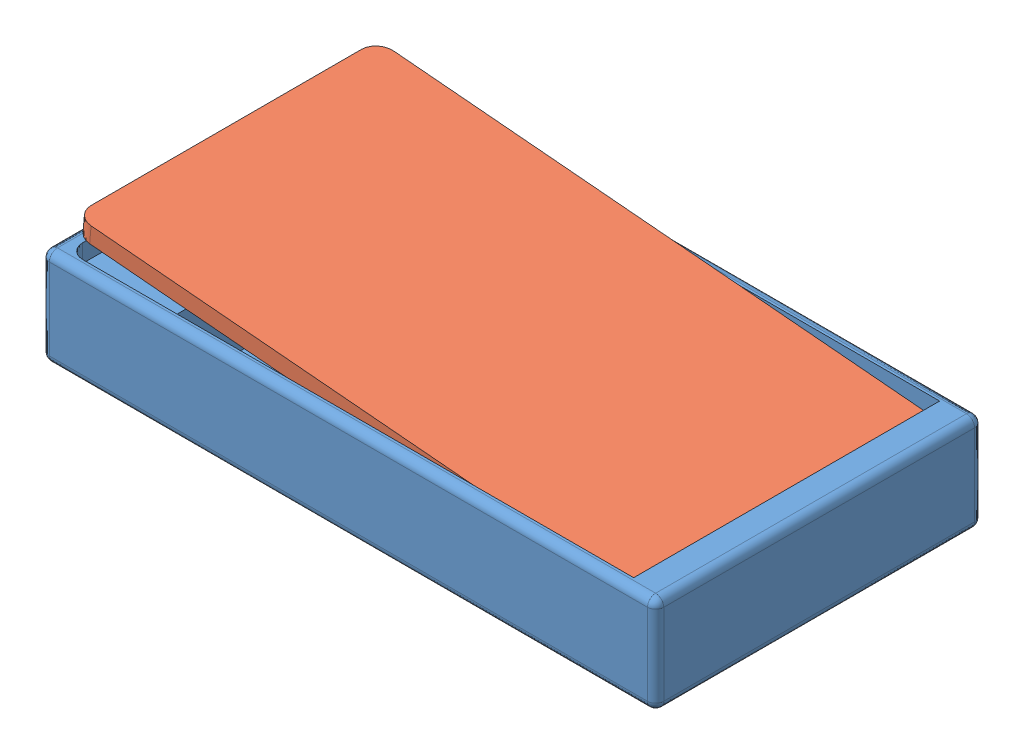
SolidWorks assembly 装配体1, configuration 默认. Lengths in mm.
Overall size (75.5 16.08 40.2).
2 component instances, 2 part files, 2 mates.
Components (placement in the parent):
- roof-1: roof [默认] at (-17.3616 -73.6475 -3.8299) size (75.5 12 40.2)
- roof-1-1: roof-1 [默认] at (-18.2363 -72.368 -3.8299) x (0.996195 -0.087156 0) z (0 0 1) size (70.6 3.8 37.2)
Mates (geometry in assembly coordinates):
- 重合1: coincident anti-aligned: plane of roof-1 through (-17.4482 -72.437 -43.2837) normal (0.087156 0.996195 0); plane of roof-1-1 through (-18.2363 -72.368 -3.8299) normal (-0.087156 -0.996195 0)
- 距离1: distance = 0.2 mm anti-aligned: plane of roof-1-1 through (-18.062 -70.3756 -22.4299) normal (0 0 -1); plane of roof-1 through (-17.3616 -71.4475 -22.6299) normal (0 0 1)
